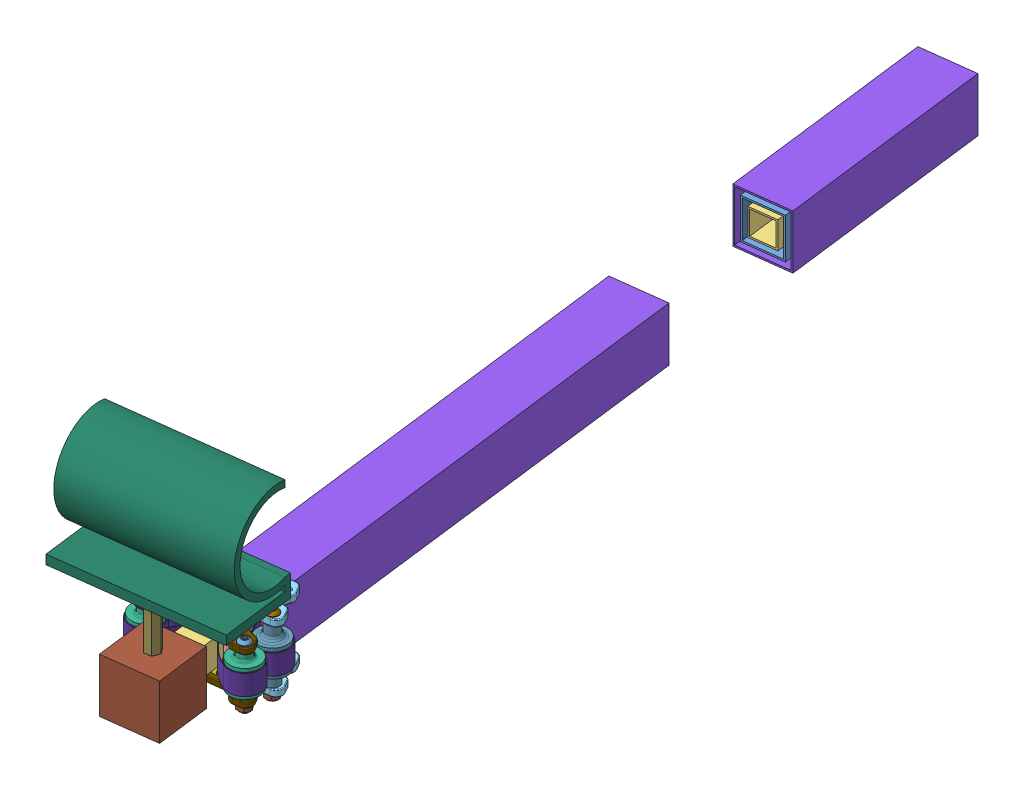
SolidWorks assembly climber prototype, configuration Default. Lengths in mm.
Overall size (269.94 253.74 951.32).
100 component instances, 33 part files, 14 mates.
Components (placement in the parent):
- 2 x 2 Inch Stage.stp-1: 2 x 2 Inch Stage.stp [Default] at (1113.4745 353.0023 985.2524) size (183.93 74.15 806.3)
  - 1.5_inch_stage.stp-1: 1.5_inch_stage.stp [Default] at (-107.3783 0 -858.4701) size (133.34 47.37 731.79)
    - 1.5x1.5 bar.stp-1: 1.5x1.5 bar.stp [Default] at (575.8182 404.7167 1377.5179) x (-0.992268 0 0.124114) z (-0.124114 0 -0.992268) size (38.1 38.1 711.2)
    - 2x2StageInternalEndBlock.stp-1: 2x2StageInternalEndBlock.stp [Default] at (413.7616 573.8056 681.0462) x (-0.992268 0 0.124114) z (-0.124114 0 -0.992268) size (47.37 47.37 40.64)
    - 94615A115_Brass Flanged Screw-to-Expand Inserts (1).stp-1: 94615A115_Brass Flanged Screw-to-Expand Inserts (1).stp [Default] at (431.7042 573.8056 688.4011) x (0.114575 0.384452 0.916007) z (-0.047716 0.923145 -0.381479) size (7.92 9.53 7.92)
    - 97763A231_18-8 Stainless Steel Button Head Hex Drive Screws.stp-1: 97763A231_18-8 Stainless Steel Button Head Hex Drive Screws.stp [Default] at (398.9269 573.8691 692.501) x (0.124114 0.000773 0.992268) z (-0.992268 0 0.124114) size (9.17 9.17 12.09)
  - 2x2ClimberPlateAssemblyNew.stp-1: 2x2ClimberPlateAssemblyNew.stp [Default] at (310.1471 56.4224 225.65) x (0.992268 0 -0.124114) z (0.124114 0 0.992268) size (102.18 13.04 44.45)
    - 2x2NewClimberPlateConcept.stp-1: 2x2NewClimberPlateConcept.stp [Default] at (71.6924 542.7705 -285.0056) x (-1 0 0) z (0 1 0) size (102.18 44.45 8.76)
    - 98381A545_ALLOY STEEL DOWEL PIN.stp-1: 98381A545_ALLOY STEEL DOWEL PIN.stp [Default] at (46.4194 542.6435 281.8589) x (-1 0 0) z (0 -0.467381 0.884056) size (34.92 6.35 6.35)
    - TTB-0027_.50OD_.25ID_.188WD.stp-1: TTB-0027_.50OD_.25ID_.188WD.stp [Default] at (31.3382 542.6435 281.8589) x (0 0.013886 0.999904) z (-1 0 0) size (12.7 12.7 4.76)
    - TTB-0027_.50OD_.25ID_.188WD.stp-2: TTB-0027_.50OD_.25ID_.188WD.stp [Default] at (61.5007 542.6435 281.8589) x (0 0.005291 0.999986) z (-1 0 0) size (12.7 12.7 4.76)
  - 2x2ClimberPlateAssemblyNew.stp-2: 2x2ClimberPlateAssemblyNew.stp [Default] at (402.0161 1091.1635 214.1589) x (-0.992268 0 0.124114) z (0.124114 0 0.992268) size (102.18 13.04 44.45)
    - 2x2NewClimberPlateConcept.stp-1: 2x2NewClimberPlateConcept.stp [Default] at (71.6924 542.7705 -285.0056) x (-1 0 0) z (0 1 0) size (102.18 44.45 8.76)
    - 98381A545_ALLOY STEEL DOWEL PIN.stp-1: 98381A545_ALLOY STEEL DOWEL PIN.stp [Default] at (46.4194 542.6435 281.8589) x (-1 0 0) z (0 -0.467381 0.884056) size (34.92 6.35 6.35)
    - TTB-0027_.50OD_.25ID_.188WD.stp-1: TTB-0027_.50OD_.25ID_.188WD.stp [Default] at (31.3382 542.6435 281.8589) x (0 0.013886 0.999904) z (-1 0 0) size (12.7 12.7 4.76)
    - TTB-0027_.50OD_.25ID_.188WD.stp-2: TTB-0027_.50OD_.25ID_.188WD.stp [Default] at (61.5007 542.6435 281.8589) x (0 0.005291 0.999986) z (-1 0 0) size (12.7 12.7 4.76)
  - 2x2 Box.stp-1: 2x2 Box.stp [Default] at (320.6921 548.3929 -267.6788) x (-0.992268 0 0.124114) z (0.124114 0 0.992268) size (50.8 50.8 762)
  - 91255A529_NO THREADS_Button Head Hex Drive Screw (1).stp-1: 91255A529_NO THREADS_Button Head Hex Drive Screw (1).stp [Default] at (366.1553 609.0227 504.1716) x (0.396837 0 -0.917889) z (0 1 0) size (11.1 11.1 73.2)
  - 90044A515_Black-Oxide Alloy Steel Socket Head Screw.stp-1: 90044A515_Black-Oxide Alloy Steel Socket Head Screw.stp [Default] at (410.673 605.6699 482.6046) x (0.993633 0 -0.112668) z (0 1 0) size (6.86 6.86 74.15)
  - 90044A515_Black-Oxide Alloy Steel Socket Head Screw.stp-2: 90044A515_Black-Oxide Alloy Steel Socket Head Screw.stp [Default] at (367.8773 605.6699 487.9575) x (0.430705 0 0.902493) z (0 1 0) size (6.86 6.86 74.15)
  - 91255A529_NO THREADS_Button Head Hex Drive Screw (1).stp-2: 91255A529_NO THREADS_Button Head Hex Drive Screw (1).stp [Default] at (351.7432 609.0227 521.973) x (-0.099638 0 0.995024) z (0 1 0) size (11.1 11.1 73.2)
  - 91255A529_NO THREADS_Button Head Hex Drive Screw (1).stp-3: 91255A529_NO THREADS_Button Head Hex Drive Screw (1).stp [Default] at (434.6883 609.0227 511.5981) x (1 0 0) z (0 1 0) size (11.1 11.1 73.2)
  - 91255A529_NO THREADS_Button Head Hex Drive Screw (1).stp-4: 91255A529_NO THREADS_Button Head Hex Drive Screw (1).stp [Default] at (416.3356 609.0227 497.895) x (0.998718 0 -0.050617) z (0 1 0) size (11.1 11.1 73.2)
  - TTB-0027_.50OD_.25ID_.188WD.stp-1: TTB-0027_.50OD_.25ID_.188WD.stp [Default] at (416.3356 557.2004 497.895) x (-0.032207 0 0.999481) z (0 1 0) size (12.7 12.7 4.76)
  - TTB-0027_.50OD_.25ID_.188WD.stp-2: TTB-0027_.50OD_.25ID_.188WD.stp [Default] at (416.3356 590.4617 497.895) x (-0.065423 0 0.997858) z (0 1 0) size (12.7 12.7 4.76)
  - TTB-0027_.50OD_.25ID_.188WD.stp-3: TTB-0027_.50OD_.25ID_.188WD.stp [Default] at (366.1553 557.2004 504.1716) x (-0.065423 0 0.997858) z (0 1 0) size (12.7 12.7 4.76)
  - TTB-0027_.50OD_.25ID_.188WD.stp-4: TTB-0027_.50OD_.25ID_.188WD.stp [Default] at (366.1553 590.4617 504.1716) x (-0.065423 0 0.997858) z (0 1 0) size (12.7 12.7 4.76)
  - 90101A230_18-8 Stainless Steel Thin Nylon-Insert Locknut.stp-1: 90101A230_18-8 Stainless Steel Thin Nylon-Insert Locknut.stp [Default] at (434.6883 541.9159 511.5981) x (0.797272 0 -0.60362) z (-0.60362 0 -0.797272) size (11.11 5.2 12.83)
  - 90101A230_18-8 Stainless Steel Thin Nylon-Insert Locknut.stp-2: 90101A230_18-8 Stainless Steel Thin Nylon-Insert Locknut.stp [Default] at (416.3356 541.9159 497.895) x (0.921386 0 0.388648) z (0.388648 0 -0.921386) size (11.11 5.2 12.83)
  - 90101A230_18-8 Stainless Steel Thin Nylon-Insert Locknut.stp-3: 90101A230_18-8 Stainless Steel Thin Nylon-Insert Locknut.stp [Default] at (351.7432 541.9159 521.973) x (0.797272 0 -0.60362) z (-0.60362 0 -0.797272) size (11.11 5.2 12.83)
  - 90101A230_18-8 Stainless Steel Thin Nylon-Insert Locknut.stp-4: 90101A230_18-8 Stainless Steel Thin Nylon-Insert Locknut.stp [Default] at (366.1553 541.9159 504.1716) x (0.797272 0 -0.60362) z (-0.60362 0 -0.797272) size (11.11 5.2 12.83)
  - QuaterInchTelescopingSpacer.stp-1: QuaterInchTelescopingSpacer.stp [Default] at (391.2422 599.1929 504.1716) x (1 0 0) z (0 -1 0) size (9.27 9.27 6.35)
  - QuaterInchTelescopingSpacer.stp-2: QuaterInchTelescopingSpacer.stp [Default] at (391.2422 554.8191 504.1844) x (1 0 0.000511) z (0 -1 0) size (9.27 9.27 6.35)
  - 1.122InchTelescopingSpacer.stp-1: 1.122InchTelescopingSpacer.stp [Default] at (391.2422 588.0804 504.1716) x (1 0 0) z (0 -1 0) size (8.76 8.76 28.5)
  - QuaterInchTelescopingSpacer.stp-3: QuaterInchTelescopingSpacer.stp [Default] at (440.4399 599.1929 504.8475) x (0.96083 0 0.277139) z (0 -1 0) size (9.27 9.27 6.35)
  - QuaterInchTelescopingSpacer.stp-4: QuaterInchTelescopingSpacer.stp [Default] at (409.5553 554.8191 522.0482) x (-0.270275 0 0.962783) z (0 -1 0) size (9.27 9.27 6.35)
  - 94615A115_Brass Flanged Screw-to-Expand Inserts (1).stp-1: 94615A115_Brass Flanged Screw-to-Expand Inserts (1).stp [Default] at (290.8052 573.8056 -165.8762) x (0.123955 0.050546 0.991) z (0.006274 -0.998722 0.050156) size (7.92 9.53 7.92)
  - 97763A231_18-8 Stainless Steel Button Head Hex Drive Screws.stp-1: 97763A231_18-8 Stainless Steel Button Head Hex Drive Screws.stp [Default] at (323.7085 573.8691 -169.9917) x (-0.124114 0 -0.992268) z (0.992268 0 -0.124114) size (9.17 9.17 12.09)
  - 1.122InchTelescopingSpacer.stp-2: 1.122InchTelescopingSpacer.stp [Default] at (441.4226 588.0804 497.895) x (1 0 0) z (0 -1 0) size (8.76 8.76 28.5)
  - 1InchCFSpringRetentionSpacer_BaseStage.stp-1: 1InchCFSpringRetentionSpacer_BaseStage.stp [Default] at (351.7432 564.2679 521.973) x (1 0 0) z (0 -1 0) size (27.94 27.94 15.88)
  - 1InchCFSpringRetentionSpacer_BaseStage.stp-2: 1InchCFSpringRetentionSpacer_BaseStage.stp [Default] at (434.6883 583.3179 511.5981) x (-0.043542 0 0.999052) z (0 1 0) size (27.94 27.94 15.88)
  - 1InchCFSpringRetentionSpacer_BaseStage.stp-3: 1InchCFSpringRetentionSpacer_BaseStage.stp [Default] at (351.7432 583.3179 521.973) x (1 0 0) z (0 1 0) size (27.94 27.94 15.88)
  - 1InchCFSpringRetentionSpacer_BaseStage.stp-4: 1InchCFSpringRetentionSpacer_BaseStage.stp [Default] at (434.6883 564.2679 511.5981) x (0.999991 0 -0.00417) z (0 -1 0) size (27.94 27.94 15.88)
  - 90101A009_18-8 Stainless Steel Thin Nylon-Insert Locknut (1).stp-1: 90101A009_18-8 Stainless Steel Thin Nylon-Insert Locknut (1).stp [Default] at (368.252 541.9159 487.9106) x (0.797272 0 -0.60362) z (-0.60362 0 -0.797272) size (8.73 4.37 10.08)
  - 9293K56_SpringRoller.stp-1: 9293K56_SpringRoller.stp [Default] at (351.7432 564.2679 521.973) x (0.41705 0 -0.908884) z (0 1 0) size (20.07 20.07 19.05)
  - 9293K56_SpringRoller.stp-2: 9293K56_SpringRoller.stp [Default] at (434.6883 583.3179 511.5981) x (0.41705 0 0.908884) z (0 -1 0) size (20.07 20.07 19.05)
  - 9293K56_Constant-Force Spring.stp-1: 9293K56_Constant-Force Spring.stp [Default] at (434.7326 573.7929 511.5599) x (0 -1 0) z (-0.934501 0 0.355959) size (19.06 41.04 33.21)
  - 9293K56_Constant-Force Spring.stp-2: 9293K56_Constant-Force Spring.stp [Default] at (351.6902 573.7929 521.9484) x (0 1 0) z (0.996341 0 0.085466) size (19.06 41.04 33.21)
  - 90101A009_18-8 Stainless Steel Thin Nylon-Insert Locknut (1).stp-2: 90101A009_18-8 Stainless Steel Thin Nylon-Insert Locknut (1).stp [Default] at (410.673 541.9159 482.6046) x (0.797272 0 -0.60362) z (-0.60362 0 -0.797272) size (8.73 4.37 10.08)
- Stage 2 BOM - 1.5 inch to 1 inch Kit.stp-1: Stage 2 BOM - 1.5 inch to 1 inch Kit.stp [Default] at (1071.3002 772.575 539.439) x (0.992268 0 -0.124114) z (0.124114 0 0.992268) size (125.22 66.32 768.66)
  - 1.5ClimberPlateNewDesign.stp-1: 1.5ClimberPlateNewDesign.stp [Default] at (293.5653 129.5314 1017.7273) x (1 0 0) z (0 1 0) size (98.65 41.27 8)
  - 1.5ClimberPlateNewDesign.stp-2: 1.5ClimberPlateNewDesign.stp [Default] at (331.6653 179.0614 1017.7273) x (-1 0 0) z (0 -1 0) size (98.65 41.27 8)
  - 91255A528_NO THREADS_Button Head Hex Drive Screw.stp-1: 91255A528_NO THREADS_Button Head Hex Drive Screw.stp [Default] at (354.2078 182.4142 1039.3173) x (0.997583 0 0.069478) z (0 1 0) size (11.1 11.1 60.5)
  - 91255A528_NO THREADS_Button Head Hex Drive Screw.stp-2: 91255A528_NO THREADS_Button Head Hex Drive Screw.stp [Default] at (331.551 182.4142 1025.9823) x (1 0 0.000115) z (0 1 0) size (11.1 11.1 60.5)
  - 91255A528_NO THREADS_Button Head Hex Drive Screw.stp-3: 91255A528_NO THREADS_Button Head Hex Drive Screw.stp [Default] at (293.6796 182.4142 1025.9823) x (0.942114 0 0.335293) z (0 1 0) size (11.1 11.1 60.5)
  - 91255A528_NO THREADS_Button Head Hex Drive Screw.stp-4: 91255A528_NO THREADS_Button Head Hex Drive Screw.stp [Default] at (271.0228 182.4142 1039.3173) x (1 0 0) z (0 1 0) size (11.1 11.1 60.5)
  - 98381A542_ALLOY STEEL DOWEL PIN.stp-1: 98381A542_ALLOY STEEL DOWEL PIN.stp [Default] at (312.5899 173.2194 1025.9545) x (1 0 0) z (0 -0.047568 0.998868) size (25.4 6.35 6.35)
  - 98381A542_ALLOY STEEL DOWEL PIN.stp-2: 98381A542_ALLOY STEEL DOWEL PIN.stp [Default] at (312.5899 135.3734 1025.9545) x (1 0 0) z (0 -0.129807 0.991539) size (25.4 6.35 6.35)
  - TTB-0027_.50OD_.25ID_.188WD.stp-1: TTB-0027_.50OD_.25ID_.188WD.stp [Default] at (322.7054 135.3734 1025.9545) x (0 -0.059569 0.998224) z (-1 0 0) size (12.7 12.7 4.76)
  - TTB-0027_.50OD_.25ID_.188WD.stp-2: TTB-0027_.50OD_.25ID_.188WD.stp [Default] at (302.4743 135.3734 1025.9545) x (0 0.249065 0.968487) z (-1 0 0) size (12.7 12.7 4.76)
  - TTB-0027_.50OD_.25ID_.188WD.stp-3: TTB-0027_.50OD_.25ID_.188WD.stp [Default] at (293.6796 166.19 1025.9823) x (-0.99026 0 0.139228) z (0 1 0) size (12.7 12.7 4.76)
  - TTB-0027_.50OD_.25ID_.188WD.stp-4: TTB-0027_.50OD_.25ID_.188WD.stp [Default] at (293.6796 142.2505 1025.9823) x (1 0 0) z (0 1 0) size (12.7 12.7 4.76)
  - TTB-0027_.50OD_.25ID_.188WD.stp-5: TTB-0027_.50OD_.25ID_.188WD.stp [Default] at (331.551 166.19 1025.9823) x (-0.070413 0 0.997518) z (0 1 0) size (12.7 12.7 4.76)
  - TTB-0027_.50OD_.25ID_.188WD.stp-6: TTB-0027_.50OD_.25ID_.188WD.stp [Default] at (302.4743 173.2194 1025.9545) x (0 -0.065423 0.997858) z (-1 0 0) size (12.7 12.7 4.76)
  - TTB-0027_.50OD_.25ID_.188WD.stp-7: TTB-0027_.50OD_.25ID_.188WD.stp [Default] at (322.7054 173.2194 1025.9545) x (0 0.136778 0.990602) z (-1 0 0) size (12.7 12.7 4.76)
  - TTB-0027_.50OD_.25ID_.188WD.stp-8: TTB-0027_.50OD_.25ID_.188WD.stp [Default] at (331.551 142.2505 1025.9823) x (1 0 0) z (0 1 0) size (12.7 12.7 4.76)
  - 1x1.stp-1: 1x1.stp [Default] at (299.8518 166.9329 770.3868) x (0 -1 0) z (-1 0 0) size (25.4 711.2 25.4)
  - 90101A230_18-8 Stainless Steel Thin Nylon-Insert Locknut.stp-1: 90101A230_18-8 Stainless Steel Thin Nylon-Insert Locknut.stp [Default] at (293.6796 129.5314 1025.9823) x (0.866025 0 -0.5) z (-0.5 0 -0.866025) size (11.11 5.2 12.83)
  - 90101A230_18-8 Stainless Steel Thin Nylon-Insert Locknut.stp-2: 90101A230_18-8 Stainless Steel Thin Nylon-Insert Locknut.stp [Default] at (354.2078 129.5314 1039.3173) x (-0.866025 0 -0.5) z (-0.5 0 0.866025) size (11.11 5.2 12.83)
  - 90101A230_18-8 Stainless Steel Thin Nylon-Insert Locknut.stp-3: 90101A230_18-8 Stainless Steel Thin Nylon-Insert Locknut.stp [Default] at (331.551 129.5314 1025.9823) x (0.866025 0 0.5) z (0.5 0 -0.866025) size (11.11 5.2 12.83)
  - 90101A230_18-8 Stainless Steel Thin Nylon-Insert Locknut.stp-4: 90101A230_18-8 Stainless Steel Thin Nylon-Insert Locknut.stp [Default] at (271.0228 129.5314 1039.3173) x (0.866025 0 0.5) z (0.5 0 -0.866025) size (11.11 5.2 12.83)
  - .607TelescopingSpacer.stp-1: .607TelescopingSpacer.stp [Default] at (354.9872 144.6317 1017.0327) x (0.934202 0 -0.356745) z (0 1 0) size (9.02 9.02 19.18)
  - .607TelescopingSpacer.stp-2: .607TelescopingSpacer.stp [Default] at (318.7665 144.6317 1026.006) x (1 0 0.000943) z (0 1 0) size (9.02 9.02 19.18)
  - .188TelescopingSpacer.stp-1: .188TelescopingSpacer.stp [Default] at (356.6379 173.3464 1025.9823) x (1 0 0) z (0 -1 0) size (8.81 8.81 4.78)
  - .188TelescopingSpacer.stp-2: .188TelescopingSpacer.stp [Default] at (318.7665 173.3464 1025.9823) x (1 0 0) z (0 -1 0) size (8.81 8.81 4.78)
  - .188TelescopingSpacer.stp-3: .188TelescopingSpacer.stp [Default] at (282.8338 139.8692 1048.6036) x (-0.432328 0 0.901716) z (0 -1 0) size (8.81 8.81 4.78)
  - .188TelescopingSpacer.stp-4: .188TelescopingSpacer.stp [Default] at (326.9008 139.8692 1001.3302) x (-0.18536 0 -0.982671) z (0 -1 0) size (8.81 8.81 4.78)
  - 9293K56_Constant-Force Spring.stp-1: 9293K56_Constant-Force Spring.stp [Default] at (354.2389 154.2964 1039.2678) x (0 -1 0) z (-0.788944 0 0.614465) size (19.06 41.04 33.21)
  - 1InchCFSpringRetentionSpacer.stp-1: 1InchCFSpringRetentionSpacer.stp [Default] at (271.0228 144.7714 1039.3173) x (0.41705 0 0.908884) z (0 -1 0) size (27.94 27.94 9.53)
  - 1InchCFSpringRetentionSpacer.stp-2: 1InchCFSpringRetentionSpacer.stp [Default] at (354.2078 144.7714 1039.3173) x (0.383782 0 0.923424) z (0 -1 0) size (27.94 27.94 9.53)
  - 1InchCFSpringRetentionSpacer.stp-3: 1InchCFSpringRetentionSpacer.stp [Default] at (354.2078 163.8214 1039.3173) x (0.830028 0 -0.557722) z (0 1 0) size (27.94 27.94 9.53)
  - 1InchCFSpringRetentionSpacer.stp-4: 1InchCFSpringRetentionSpacer.stp [Default] at (271.0228 163.8214 1039.3173) x (0.383782 0 -0.923424) z (0 1 0) size (27.94 27.94 9.53)
  - 9293K56_Constant-Force Spring.stp-2: 9293K56_Constant-Force Spring.stp [Default] at (270.9861 154.2964 1039.2718) x (0 1 0) z (0.855643 0 0.517566) size (19.06 41.04 33.21)
  - 9293K56_SpringRoller.stp-1: 9293K56_SpringRoller.stp [Default] at (271.0228 163.8214 1039.3173) x (0.416799 0 0.908999) z (0 -1 0) size (20.07 20.07 19.05)
  - 1x1StageInternalEndBlock.stp-1: 1x1StageInternalEndBlock.stp [Default] at (312.6153 154.2964 363.9868) x (-1 0 0) z (0 0 -1) size (34.67 34.67 40)
  - 90101A009_18-8 Stainless Steel Thin Nylon-Insert Locknut (1).stp-1: 90101A009_18-8 Stainless Steel Thin Nylon-Insert Locknut (1).stp [Default] at (327.8299 129.5314 1011.3773) x (0.866025 0 0.5) z (0.5 0 -0.866025) size (8.73 4.37 10.08)
  - 90101A009_18-8 Stainless Steel Thin Nylon-Insert Locknut (1).stp-2: 90101A009_18-8 Stainless Steel Thin Nylon-Insert Locknut (1).stp [Default] at (297.4007 129.5314 1011.3773) x (-0.866025 0 -0.5) z (-0.5 0 0.866025) size (8.73 4.37 10.08)
  - 90044A513_Black-Oxide Alloy Steel Socket Head Screw.stp-1: 90044A513_Black-Oxide Alloy Steel Socket Head Screw.stp [Default] at (297.4007 179.0614 1011.3773) x (0.353324 0 0.935501) z (0 1 0) size (10.11 10 66.32)
  - 90044A513_Black-Oxide Alloy Steel Socket Head Screw.stp-2: 90044A513_Black-Oxide Alloy Steel Socket Head Screw.stp [Default] at (327.8299 179.0614 1011.3773) x (1 0 0) z (0 1 0) size (10.11 10 66.32)
  - 94615A212_Brass Flanged Screw-to-Expand Inserts (1).stp-1: 94615A212_Brass Flanged Screw-to-Expand Inserts (1).stp [Default] at (301.9473 154.2964 373.5118) x (0 -0.59679 -0.802398) z (0 0.802398 -0.59679) size (7.14 7.14 7.14)
  - 94615A212_Brass Flanged Screw-to-Expand Inserts (1).stp-2: 94615A212_Brass Flanged Screw-to-Expand Inserts (1).stp [Default] at (323.2833 154.2964 373.5118) x (0 0.670342 -0.742052) z (0 -0.742052 -0.670342) size (7.14 7.14 7.14)
  - 97763A504_18-8 Stainless Steel Button Head Hex Drive Screws.stp-1: 97763A504_18-8 Stainless Steel Button Head Hex Drive Screws.stp [Default] at (302.0806 154.2964 373.5118) x (0 0 1) z (-1 0 0) size (7.92 7.92 10.15)
  - 97763A504_18-8 Stainless Steel Button Head Hex Drive Screws.stp-2: 97763A504_18-8 Stainless Steel Button Head Hex Drive Screws.stp [Default] at (323.0229 154.2964 373.5118) x (0 0 -1) z (1 0 0) size (7.92 7.92 10.15)
  - 1.5x1.5 bar.stp-1: 1.5x1.5 bar.stp [Default] at (386.9135 -14.856 1017.7273) x (-1 0 0) z (0 0 -1) size (38.1 38.1 711.2)
  - 9293K56_SpringRoller.stp-2: 9293K56_SpringRoller.stp [Default] at (354.2078 163.8214 1039.3173) x (0.416799 0 0.908999) z (0 -1 0) size (20.07 20.07 19.05)
- block for climber-1: block for climber [Default] at (1512.9894 926.808 1552.3982) x (0 1 0) z (0.992268 0 -0.124114) size (50.8 50.8 50.8)
- Hex shaft for climber-1: Hex shaft for climber [Default] at (1516.1419 914.108 1577.6018) x (0 1 0) z (0.992268 0 -0.124114) size (115.41 12 13.86)
- half in hex bearing for clibmer-2: half in hex bearing for clibmer [Default] at (1516.1419 1028.4613 1577.6018) x (0.992268 0 -0.124114) z (0 -1 0) size (31.12 31.12 7.93)
- wood piece for pivot in climber-1: wood piece for pivot in climber [Default] at (1516.1419 1022.058 1577.6018) x (0 1 0) z (0.992268 0 -0.124114) size (6.35 38.1 101.6)
- claw for clibmer-2: claw for clibmer [Default] at (1616.6946 1085.4418 1562.8992) x (-0.07906 -0.770864 -0.632074) z (-0.992268 0 0.124114) size (99.21 112.78 152.4)
Mates (geometry in assembly coordinates):
- Coincident4: coincident anti-aligned: plane of block for climber-1 through (1512.9894 496.9265 1552.3982) normal (0 1 0); plane of Hex shaft for climber-1 through (1516.1419 496.9265 1577.6018) normal (0 -1 0)
- Coincident5: coincident anti-aligned: plane of block for climber-1 through (1509.2673 496.9265 1578.4617) normal (0.797272 0 -0.60362); plane of Hex shaft for climber-1 through (1509.2673 611.2265 1578.4617) normal (-0.797272 0 0.60362)
- Coincident6: coincident anti-aligned: plane of block for climber-1 through (1520.3239 496.9265 1583.1255) normal (-0.921386 0 -0.388648); plane of Hex shaft for climber-1 through (1520.3239 611.2265 1583.1255) normal (0.921386 0 0.388648)
- Concentric1: concentric anti-aligned: cylinder of half in hex bearing for clibmer-2 through (1516.1419 603.3525 1577.6018) axis (0 1 0) radius 14.2875; cylinder of wood piece for pivot in climber-1 through (1516.1419 611.2265 1577.6018) axis (0 -1 0) radius 15.494
- Coincident7: coincident anti-aligned: plane of half in hex bearing for clibmer-2 through (1530.0039 604.8765 1575.8679) normal (0 1 0); plane of wood piece for pivot in climber-1 through (1516.1419 604.8765 1577.6018) normal (0 -1 0)
- Concentric2: concentric anti-aligned: circle of Hex shaft for climber-1; circle of half in hex bearing for clibmer-2
- Coincident8: coincident anti-aligned: plane of wood piece for pivot in climber-1 through (1516.1419 611.2265 1577.6018) normal (0 1 0); plane of claw for clibmer-2 through (1463.3703 611.2265 1565.0041) normal (0 -1 0)
- Coincident9: coincident aligned: plane of wood piece for pivot in climber-1 through (1564.1847 611.2265 1552.3941) normal (-0.124114 0 -0.992268); plane of claw for clibmer-2 through (1614.592 668.2604 1546.0891) normal (-0.124114 0 -0.992268)
- Coincident10: coincident aligned: plane of wood piece for pivot in climber-1 through (1463.3703 611.2265 1565.0041) normal (-0.992268 0 0.124114); plane of claw for clibmer-2 through (1465.4729 668.2604 1581.8141) normal (-0.992268 0 0.124114)
- Coincident14: coincident anti-aligned: plane of Stage 2 BOM - 1.5 inch to 1 inch Kit.stp-1/1x1.stp-1 through (1502.2791 939.508 1569.0966) normal (0.124114 0 0.992268); plane of block for climber-1 through (1514.8809 509.6265 1567.5204) normal (-0.124114 0 -0.992268)
- Parallel3: parallel aligned: plane of Hex shaft for climber-1 through (1523.0165 611.2265 1576.7419) normal (0.797272 0 -0.60362); plane of half in hex bearing for clibmer-2 through (1508.8662 603.3525 1578.5119) normal (0.797272 0 -0.60362)
- Coincident16: coincident anti-aligned: plane of Hex shaft for climber-1 through (1516.1419 1028.408 1577.6018) normal (0 1 0); plane of claw for clibmer-2 through (1463.3703 1028.408 1565.0041) normal (0 -1 0)
- Coincident17: coincident anti-aligned: plane of Stage 2 BOM - 1.5 inch to 1 inch Kit.stp-1/1x1.stp-1 through (1527.4827 939.508 1565.9441) normal (0.992268 0 -0.124114); plane of block for climber-1 through (1527.4827 914.108 1565.9441) normal (-0.992268 0 0.124114)
- Coincident18: coincident anti-aligned: plane of Stage 2 BOM - 1.5 inch to 1 inch Kit.stp-1/1x1.stp-1 through (1502.2791 914.108 1569.0966) normal (0 -1 0); plane of block for climber-1 through (1527.4827 914.108 1565.9441) normal (0 1 0)
